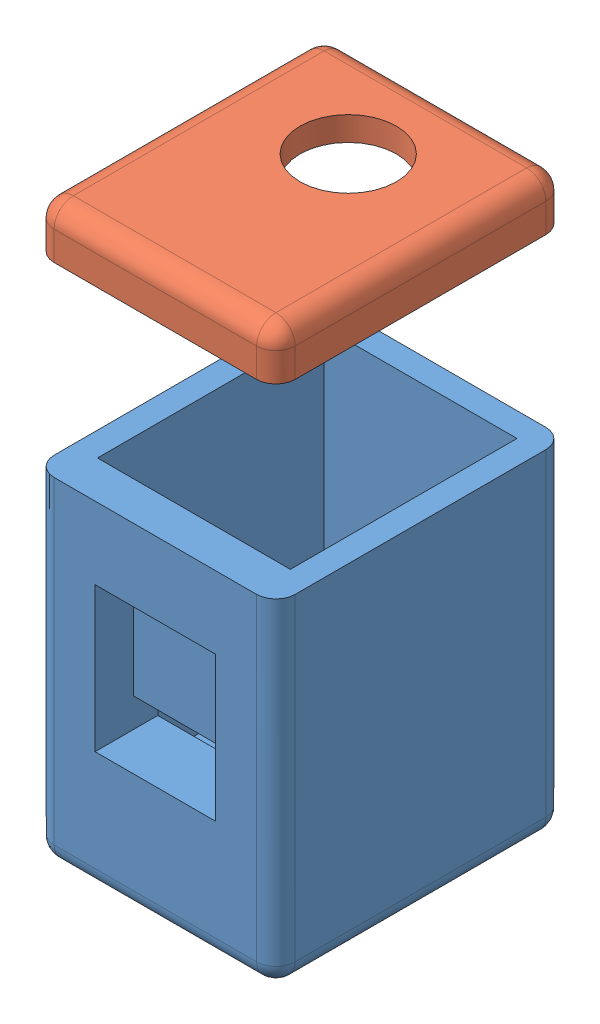
SolidWorks assembly Assem1, configuration Default. Lengths in mm.
Overall size (25 59.3 30).
2 component instances, 2 part files, 4 mates.
Components (placement in the parent):
- Part1fin2-1: Part1fin2 [Default] at (14.0274 -31.8937 2.3768) size (25 35 30)
- Part2-1: Part2 [Default] at (14.0274 27.4072 2.3768) x (-1 0 0) z (0 0 1) size (25 7.5 30)
Mates (geometry in assembly coordinates):
- Parallel1: parallel aligned: plane of Part1fin2-1 through (1.5274 -26.8937 17.3768) normal (-1 0 0); plane of Part2-1 through (1.5274 24.9072 -12.6232) normal (-1 0 0)
- Parallel3: parallel aligned: plane of Part1fin2-1 through (26.5274 -26.8937 17.3768) normal (1 0 0); plane of Part2-1 through (26.5274 24.9072 -12.6232) normal (1 0 0)
- Coincident6: coincident anti-aligned: plane of Part1fin2-1 through (4.0274 0.5063 13.3768) normal (0 0 -1); plane of Part2-1 through (23.7274 19.9072 13.3768) normal (0 0 1)
- Width1: width anti-aligned: plane of Part2-1 through (23.7274 19.9072 10.8768) normal (1 0 0); plane of Part1fin2-1 through (4.3274 19.9072 10.8768) normal (-1 0 0); plane of Part2-1 through (24.0274 3.1063 -10.1232) normal (-1 0 0); plane of Part1fin2-1 through (4.0274 3.1063 -10.1232) normal (1 0 0)
